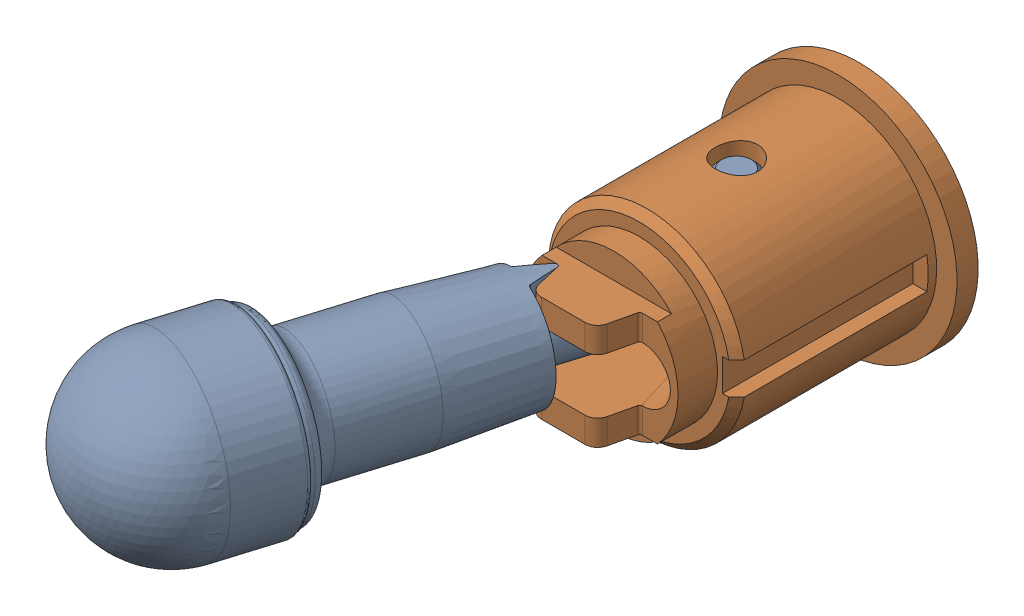
SolidWorks assembly MS Toggle Switch Locking D Ref v4, configuration Default. Lengths in mm.
Overall size (21.75 14.29 40.02).
2 component instances, 2 part files, 0 mates.
Components (placement in the parent):
- Toggle Lever Locking Round Ref-1: Toggle Lever Locking Round Ref [Default] at (19.3083 -22.352 -4.2421) x (0 1 0) z (-0.292372 0 0.956305) size (10.67 10.67 36.48)
- Toggle Threads Locking Ref-1: Toggle Threads Locking Ref [Default] at (17.526 -22.352 -4.5085) x (0 1 0) z (0 0 1) size (14.29 14.29 17.78)
